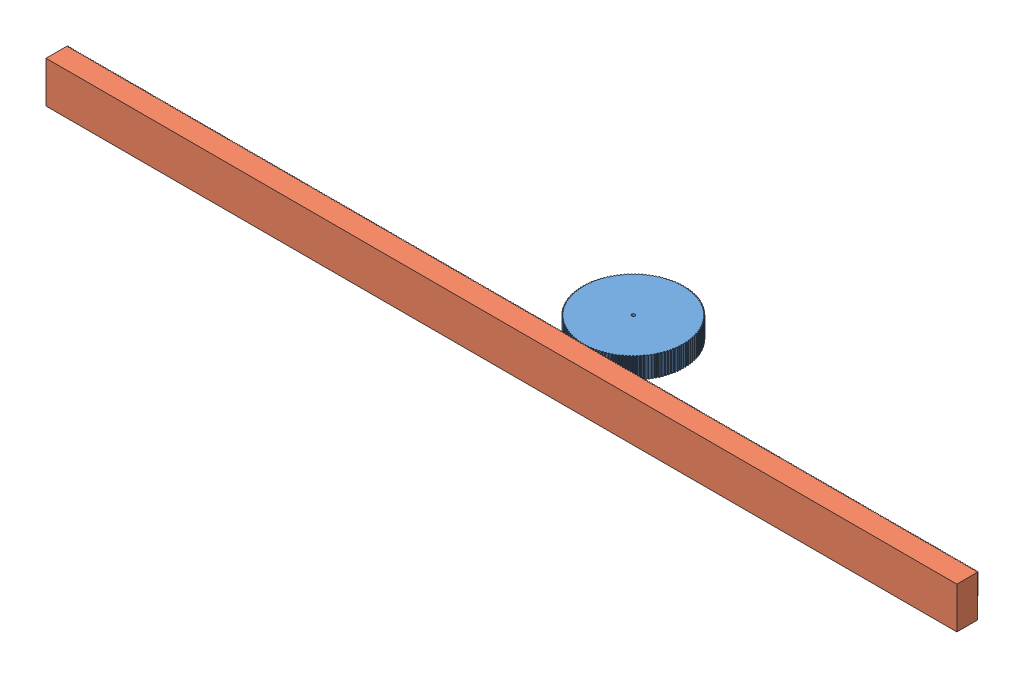
SolidWorks assembly Assem3, configuration Default. Lengths in mm.
Overall size (550 25 86.16).
2 component instances, 2 part files, 7 mates.
Components (placement in the parent):
- pinion-1: pinion [Default] at (34.4363 -12.5 32.5287) x (0.671253 0 0.741228) z (-0.741228 0 0.671253) size (60.99 12.5 61)
- rack of arm-1: rack of arm [Default] at (-2.1808 0 63.0487) x (-1 0 0) z (0 0 1) size (550 25 13)
Mates (geometry in assembly coordinates):
- Concentric2: concentric aligned: circle of pinion-1; circle of assembly
- Parallel1: parallel anti-aligned: line of rack of arm-1 through (272.8192 0 75.5487) axis (-1 0 0); line of assembly
- Distance2: distance = 43.02 mm: line of rack of arm-1 through (272.8192 0 75.5487) axis (-1 0 0); line of assembly
- Coincident4: coincident aligned: plane of pinion-1 through (34.4363 0 32.5287) normal (0 1 0); plane of rack of arm-1 through (-2.1808 0 63.0487) normal (0 1 0)
- Coincident5: coincident aligned: plane of pinion-1 through (34.4363 0 32.5287) normal (0 1 0); circle of assembly
- RackPinionMate5: rack pinion = 60.011 mm: line of rack of arm-1 through (272.8192 0 75.5487) axis (-1 0 0); cylinder of pinion-1 through (34.4363 0 32.5287) axis (0 -1 0) radius 1
- Parallel8: parallel aligned: plane of pinion-1; plane of rack of arm-1 through (-371.3239 -25 75.5487) normal (0 0 1)
